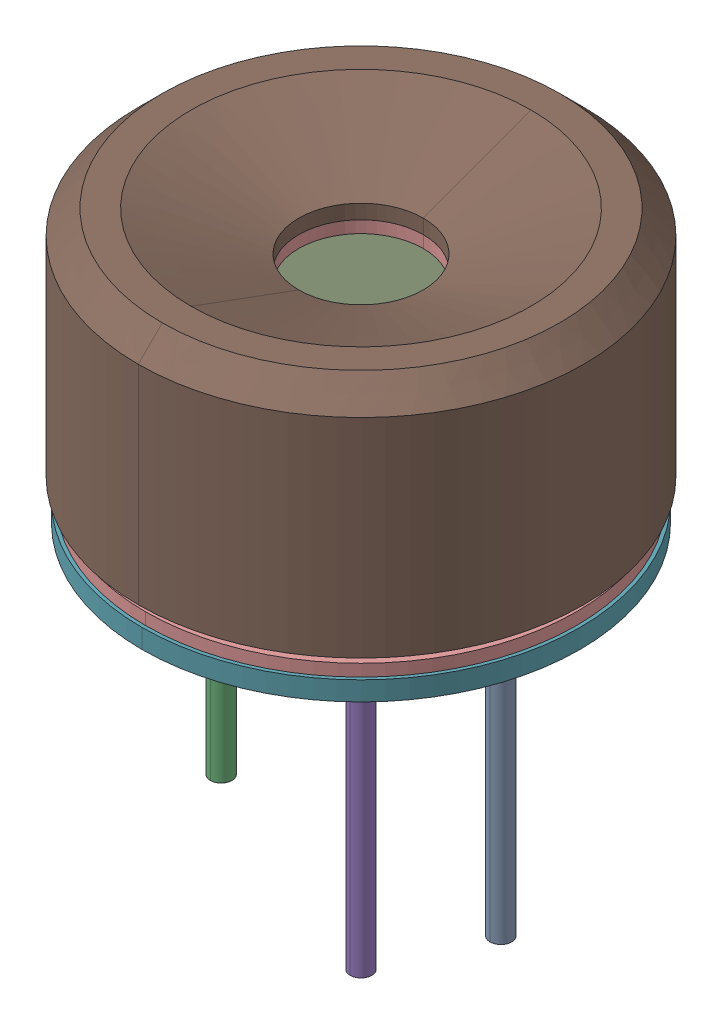
SolidWorks assembly MLX90640_120__APERTURE_ANY_ASM.stp, configuration Default. Lengths in mm.
Overall size (9.67 11.7 9.3).
12 component instances, 7 part files, 0 mates.
Components (placement in the parent):
- ASM0001_ASM.stp-1: ASM0001_ASM.stp [Default] at (8.6033 12.0231 10.0463) size (9.59 7.92 9.14)
  - PRT0005.stp-1: PRT0005.stp [Default] at (3.2095 -9.0643 9.2292) size (0.7 6.15 0.7)
  - PRT0006.stp-1: PRT0006.stp [Default] at (2.3542 -3.1643 11.2939) size (1.12 1.62 1.12)
  - PRT0007.stp-1: PRT0007.stp [Default] at (-2.6305 -9.0643 9.2292) size (0.45 7.92 0.45)
  - PRT0007.stp-2: PRT0007.stp [Default] at (-1.7753 -9.0643 7.1644) size (0.45 7.92 0.45)
  - PRT0007.stp-3: PRT0007.stp [Default] at (2.3542 -9.0643 11.2939) size (0.45 7.92 0.45)
  - PRT0006.stp-2: PRT0006.stp [Default] at (-2.6305 -3.1643 9.2292) size (1.12 1.62 1.12)
  - PRT0008.stp-1: PRT0008.stp [Default] at (0.2895 -3.0643 9.2292) size (9.59 1.52 9.14)
  - PRT0006.stp-3: PRT0006.stp [Default] at (-1.7753 -3.1643 7.1644) size (1.12 1.62 1.12)
- PRT0009.stp-1: PRT0009.stp [Default] at (8.8928 12.7788 19.2755) size (2.6 0.5 2.6)
- PRT0010.stp-1: PRT0010.stp [Default] at (8.8928 9.3588 19.2755) size (9 4.17 9)
- 90640-120X30-APPERTURE_ANY.stp-1: 90640-120X30-APPERTURE_ANY.stp [Default] at (8.8928 9.8088 19.2755) size (9.3 4.85 9.3)
